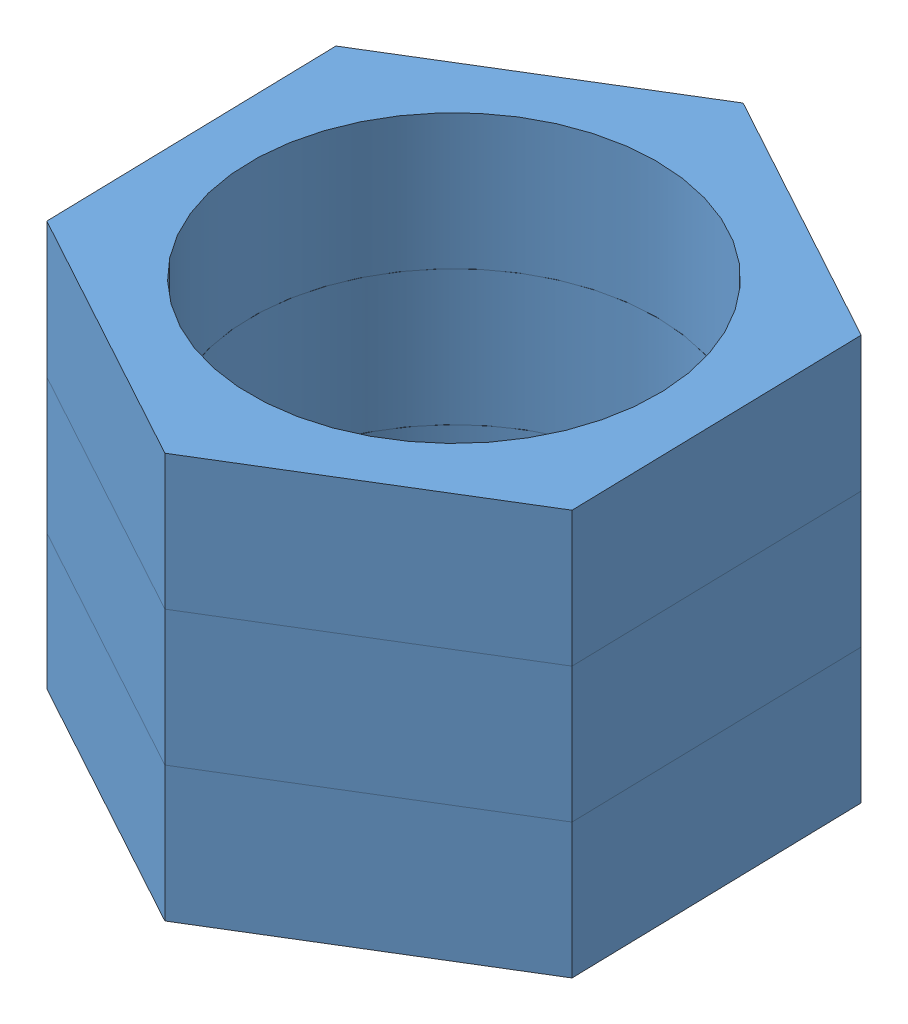
SolidWorks assembly triple_hex_nut, configuration Default. Lengths in mm.
Overall size (28.86 15 28.06).
3 component instances, 1 part files, 6 mates.
Components (placement in the parent):
- hex_nut-1: hex_nut [Default] at (6.7021 7.5775 20.2472) size (19.26 5 21.93)
- hex_nut-2: hex_nut [Default] at (6.7021 17.5775 20.2472) x (0.5 0 0.866025) z (-0.866025 0 0.5) size (19.26 5 21.93)
- hex_nut-3: hex_nut [Default] at (6.7021 17.5775 20.2472) x (0.540724 0 0.8412) z (0.8412 0 -0.540724) size (19.26 5 21.93)
Mates (geometry in assembly coordinates):
- Coincident1: coincident: point of hex_nut-1; point of hex_nut-3
- Coincident2: coincident: point of hex_nut-1; point of hex_nut-3
- Coincident3: coincident: point of hex_nut-1; point of hex_nut-3
- Coincident5: coincident: point of hex_nut-2; point of hex_nut-3
- Coincident6: coincident: point of hex_nut-2; point of hex_nut-3
- Coincident7: coincident: point of hex_nut-2; point of hex_nut-3
